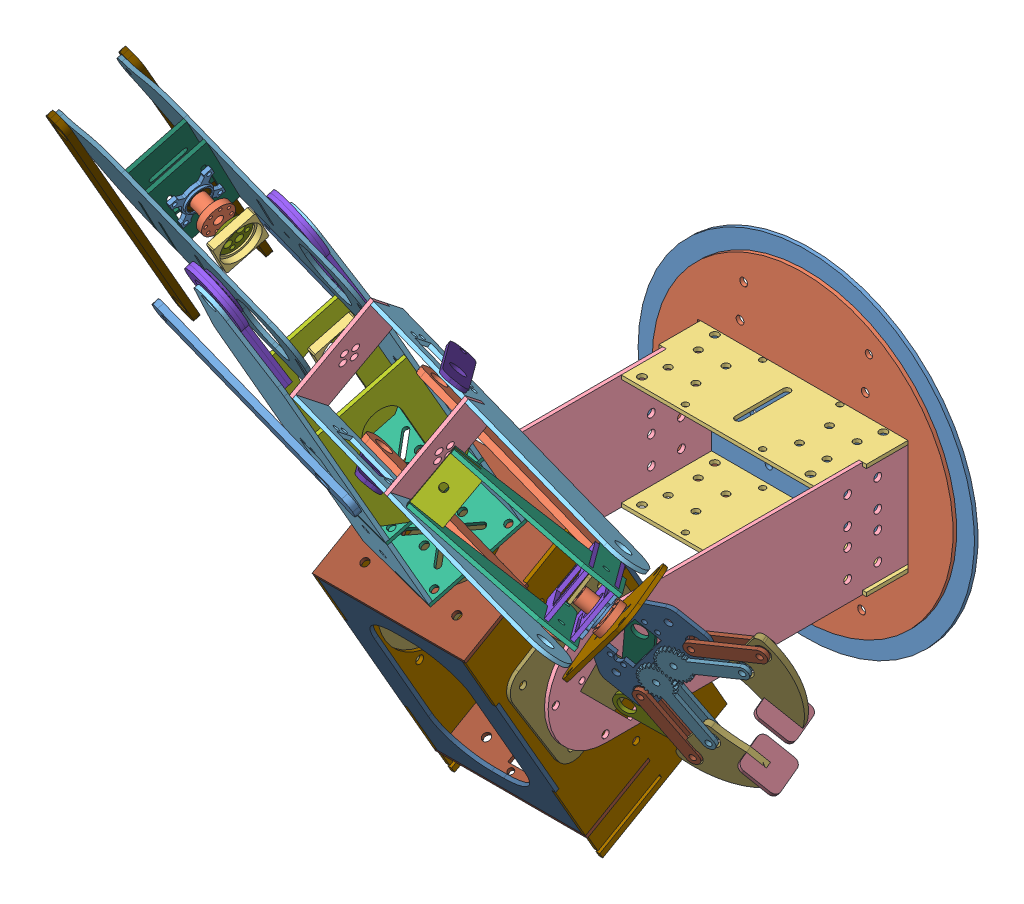
SolidWorks assembly arm, configuration Default. Lengths in mm.
Overall size (626.3 598.27 562.11).
77 component instances, 38 part files, 173 mates.
Components (placement in the parent):
- base2-1: base2 [Default] at origin size (279.4 279.4 3)
- base1-2: base1 [Default] at (0 0 3) size (250 250 3)
- base3-1: base3 [Default] at (1.3 -44.4 40.5) x (1 0 0) z (0 -1 0) size (172.4 75 3.1)
- base4-1: base4 [Default] at (81.3 0.125 254.1969) x (0 0 -1) z (1 0 0) size (298.82 95.25 3.1)
- base3-3: base3 [Default] at (1.3 47.75 40.5) x (1 0 0) z (0 -1 0) size (172.4 75 3.1)
- base4-3: base4 [Default] at (-81.8 0.14 254.1969) x (0 0 -1) z (1 0 0) size (298.82 95.25 3.1)
- upper_arm1-1: upper_arm1 [Default] at (-4.9605 223.8593 421.726) x (-0.978247 0.103059 -0.180031) z (-0.207442 -0.486002 0.848982) size (70 324.63 3.1)
- upper_arm2_(1,2)-1: upper_arm2_(1,2) [motor] at (2.3 89.3627 305.2813) x (0.207442 0.486002 -0.848982) z (0 0.86786 0.496809) size (76.2 70 3.1)
- upper_arm3-1: upper_arm3 [Default] at (36.5387 202.9167 378.6516) x (0 -0.86786 -0.496809) z (-0.978247 0.103059 -0.180031) size (120 70 3.1)
- upper_arm4-1: upper_arm4 [Default] at (-4.9605 344.9909 491.0681) x (0.978146 -0.115516 0.172876) z (0.207442 0.486002 -0.848982) size (70 90 3.1)
- shoulder1-1: shoulder1 [Default] at (-60.8 0.125 254.1969) x (0 -0.86786 -0.496809) z (1 0 0) size (230.3 120 3.1)
- shoulder2-1: shoulder2 [Default] at (2.3 21.537 197.3187) x (0 -0.86786 -0.496809) z (0 -0.496809 0.86786) size (200 126.2 3.1)
- shoulder3_(1,2)-1: shoulder3_(1,2) [motor] at (2.3 -97.7479 198.1693) x (1 0 0) z (0 0.86786 0.496809) size (126.2 120 3.1)
- shoulder1-2: shoulder1 [Default] at (62.3 0.125 254.1969) x (0 -0.86786 -0.496809) z (1 0 0) size (230.3 120 3.1)
- shoulder2-2: shoulder2 [Default] at (2.3 -38.0801 301.4619) x (0 -0.86786 -0.496809) z (0 0.496809 -0.86786) size (200 126.2 3.1)
- shoulder3_(1,2)-2: shoulder3_(1,2) [Default] at (2.3 78.5145 299.0712) x (1 0 0) z (0 0.86786 0.496809) size (126.2 120 3.1)
- upper_arm1-2: upper_arm1 [Default] at (10.2036 259.386 359.6655) x (-0.978247 0.103059 -0.180031) z (-0.207442 -0.486002 0.848982) size (70 324.63 3.1)
- upper_arm2_(1,2)-2: upper_arm2_(1,2) [motor] at (2.3 154.4522 342.5419) x (-0.207442 -0.486002 0.848982) z (0 -0.86786 -0.496809) size (76.2 70 3.1)
- upper_arm3-2: upper_arm3 [Default] at (-28.9061 209.8114 366.6075) x (0 -0.86786 -0.496809) z (-0.978247 0.103059 -0.180031) size (120 70 3.1)
- upper_arm4-2: upper_arm4 [Default] at (8.9174 377.5044 434.2712) x (0.978146 -0.115516 0.172876) z (0.207442 0.486002 -0.848982) size (70 90 3.1)
- upper_arm4-3: upper_arm4 [Default] at (-4.3382 346.4489 488.5212) x (0.978146 -0.115516 0.172876) z (0.207442 0.486002 -0.848982) size (70 90 3.1)
- upper_arm4-4: upper_arm4 [Default] at (8.2951 376.0464 436.8182) x (0.978146 -0.115516 0.172876) z (0.207442 0.486002 -0.848982) size (70 90 3.1)
- shoulder4-1: shoulder4 [Default] at (68.5 0.125 254.1969) x (0 0.849314 0.527888) z (-1 0 0) size (100 100 3.1)
- shoulder5-1: shoulder5 [Default] at (2.3 -51.6645 224.5499) x (-0.978247 0.103059 -0.180031) z (0 -0.86786 -0.496809) size (55 55 3.1)
- shoulder4-2: shoulder4 [Default] at (-60.8 0.125 254.1969) x (0 0.849314 0.527888) z (-1 0 0) size (100 100 3.1)
- elbow1-1: elbow1 [Default] at (7.0981 373.2422 441.7168) x (-0.962178 0.258021 -0.087396) z (0.207442 0.486002 -0.848982) size (242.23 80.88 3.1)
- elbow1-2: elbow1 [Default] at (-3.0728 349.4135 483.3424) x (-0.962178 0.258021 -0.087396) z (0.207442 0.486002 -0.848982) size (242.23 80.88 3.1)
- elbow2_(1,2)-1: elbow2_(1,2) [Default] at (-55.3424 377.9384 456.1984) x (-0.207442 -0.486002 0.848982) z (-0.962178 0.258021 -0.087396) size (52.13 80 3.1)
- elbow2_(1,2)-2: elbow2_(1,2) [motor] at (-76.7809 383.2969 454.0275) x (0.207442 0.486002 -0.848982) z (0.962178 -0.258021 0.087396) size (52.13 80 3.1)
- elbow3_(1,2,3)-1: elbow3_(1,2,3) [to hub] at (-21.594 368.8883 459.2638) x (0.098688 0.629162 0.770984) z (0.962178 -0.258021 0.087396) size (30 30 3.1)
- 1 x 1.245 super thin bearing-1: 1 x 1.245 super thin bearing [Default] at (-3.0728 349.4135 483.3424) x (-0.888922 -0.268661 -0.370997) z (-0.408394 0.831639 0.376286) size (32.96 6.35 32.96)
- 1 x 1.245 super thin bearing-2: 1 x 1.245 super thin bearing [Default] at (7.7412 374.7488 439.085) x (-0.313259 0.855162 0.412997) z (-0.926734 -0.180278 -0.329641) size (32.96 6.35 32.96)
- bearing mount-2: bearing mount [Default] at (-55.3424 377.9384 456.1984) x (-0.207442 -0.486002 0.848982) z (0.17658 0.835001 0.521145) size (33.27 5.08 33.27)
  - .5 x .75 non flanged bearing-1: .5 x .75 non flanged bearing [Default] at origin size (19.05 3.91 19.05)
  - 535118-1: 535118 [Default] at origin size (33.27 5.08 33.27)
- servo shaft hub-2: servo shaft hub [Default] at (-33.0439 371.9587 458.2238) x (0.109763 0.073566 -0.991232) z (0.249329 0.963334 0.099104) size (25.39 25.4 25.39)
- bearing_mount2-1: bearing_mount2 [Default] at (-18.6112 368.0884 459.5347) x (0.207442 0.486002 -0.848982) z (-0.17658 -0.835001 -0.521145) size (33.53 6.35 33.53)
  - 535178-1: 535178 [Default] at origin size (33.53 6.35 33.53)
- bearing_mount2-2: bearing_mount2 [Default] at (73.8301 343.299 467.9313) x (-0.207442 -0.486002 0.848982) z (0.17658 0.835001 0.521145) size (33.53 6.35 33.53)
  - 535178-1: 535178 [Default] at origin size (33.53 6.35 33.53)
- forearm1-1: forearm1 [Default] at (83.4518 340.7188 468.8053) x (-0.253916 -0.733199 0.630829) z (0.962178 -0.258021 0.087396) size (76.2 40 3.1)
- forearm2-1: forearm2 [Default] at (309.4718 310.6377 464.4217) x (0.098688 0.629162 0.770984) z (-0.253916 -0.733199 0.630829) size (40 244.85 3.1)
- forearm1-2: forearm1 [Default] at (169.9036 317.5356 476.6578) x (-0.253916 -0.733199 0.630829) z (0.962178 -0.258021 0.087396) size (76.2 40 3.1)
- forearm2-2: forearm2 [Default] at (290.9106 257.0408 510.5353) x (0.098688 0.629162 0.770984) z (-0.253916 -0.733199 0.630829) size (40 244.85 3.1)
- wrist1-1: wrist1 [Default] at (298.5103 268.6492 508.2224) x (-0.750272 0.560917 0.349948) z (0.253916 0.733199 -0.630829) size (128.8 82.5 3.1)
- wrist3-1: wrist3 [Default] at (222.263 341.4185 526.4428) x (-0.253916 -0.733199 0.630829) z (-0.610425 -0.384436 -0.692525) size (45 25 3.1)
- wrist1-2: wrist1 [Default] at (309.1494 299.3702 481.7906) x (-0.750272 0.560917 0.349948) z (0.253916 0.733199 -0.630829) size (128.8 82.5 3.1)
- wrist2_(1,2)-1: wrist2_(1,2) [motor] at (292.4858 286.2281 490.5617) x (-0.253916 -0.733199 0.630829) z (-0.750272 0.560917 0.349948) size (45 64.15 3.1)
- wrist2_(1,2)-2: wrist2_(1,2) [bearing] at (307.1161 275.2902 483.7377) x (-0.253916 -0.733199 0.630829) z (-0.750272 0.560917 0.349948) size (45 64.15 3.1)
- bearing mount-3: bearing mount [Default] at (307.1161 275.2902 483.7377) x (0.610425 0.384436 0.692525) z (0.253916 0.733199 -0.630829) size (33.27 5.08 33.27)
  - .5 x .75 non flanged bearing-1: .5 x .75 non flanged bearing [Default] at origin size (19.05 3.91 19.05)
  - 535118-1: 535118 [Default] at origin size (33.27 5.08 33.27)
- servo shaft hub-3: servo shaft hub [Default] at (316.0444 268.6153 479.5733) x (0.262088 -0.233607 0.936343) z (-0.606961 -0.794229 -0.028259) size (25.39 25.4 25.39)
- palm1-1: palm1 [Default] at (318.3702 266.8764 478.4885) x (-0.606961 -0.794229 -0.028259) z (-0.750272 0.560917 0.349948) size (100 55 3.1)
- palm2-1: palm2 [both] at (351.7256 241.9977 461.2898) x (0.606961 0.794229 0.028259) z (0.262088 -0.233607 0.936343) size (100.8 53.1 3.1)
- finger1-1: finger1 [Default] at (393.6016 281.5361 456.122) x (-0.943314 -0.266753 0.197488) z (0.262088 -0.233607 0.936343) size (61 11 3.1)
- finger2-1: finger2 [Default] at (355.5853 192.3989 447.8351) x (0.606937 0.794247 0.02827) z (0.262088 -0.233607 0.936343) size (48 59.12 5)
- finger3-1: finger3 [Default] at (401.3889 186.3667 435.1648) x (0.262088 -0.233607 0.936343) z (-0.606937 -0.794247 -0.02827) size (30 30 3.1)
- finger1-2: finger1 [Default] at (396.3445 279.8039 466.8836) x (-0.943314 -0.266753 0.197488) z (-0.262088 0.233607 -0.936343) size (61 11 3.1)
- finger2-2: finger2 [Default] at (404.5054 278.5927 460.9863) x (-0.606937 -0.794247 -0.02827) z (-0.262088 0.233607 -0.936343) size (48 59.12 5)
- finger3-2: finger3 [Default] at (422.0015 237.3043 444.1327) x (-0.262088 0.233607 -0.936343) z (0.606937 0.794247 0.02827) size (30 30 3.1)
- finger4-1: finger4 [mirror] at (355.5613 254.7302 463.3927) x (-0.262444 0.916438 0.3021) z (-0.262088 0.233607 -0.936343) size (26.93 68.39 3.1)
- finger4-2: finger4 [mirror] at (356.8717 253.5621 468.0745) x (0.143981 -0.949934 -0.277299) z (0.262088 -0.233607 0.936343) size (26.93 68.39 3.1)
- finger4-3: finger4 [Default] at (341.6977 233.7064 467.368) x (-0.772398 -0.632447 0.058411) z (0.262088 -0.233607 0.936343) size (26.93 68.39 3.1)
- finger4-4: finger4 [Default] at (339.5748 235.5986 459.7836) x (-0.772398 -0.632447 0.058411) z (0.262088 -0.233607 0.936343) size (26.93 68.39 3.1)
- finger1-3: finger1 [Default] at (340.443 194.4266 459.2009) x (-0.528901 0.776793 0.341843) z (-0.262088 0.233607 -0.936343) size (61 11 3.1)
- finger1-4: finger1 [Default] at (337.2422 196.0461 450.5686) x (-0.528901 0.776793 0.341843) z (0.262088 -0.233607 0.936343) size (61 11 3.1)
- link1-1: link1 [Default] at (312.9666 235.9861 453.3375) x (-0.240103 -0.955534 -0.171188) z (0.262088 -0.233607 0.936343) size (75 20 3.1)
- link2-1: link2 [Default] at (328.5353 184.6663 450.1666) x (-0.892444 0.310539 0.327276) z (-0.262088 0.233607 -0.936343) size (69 19 3.1)
- wrist_link2-1: wrist_link2 [Default] at (144.768 345.1475 438.2364) x (-0.610425 -0.384436 -0.692525) z (0.253916 0.733199 -0.630829) size (85 20 3.1)
- elbow_link1-1: elbow_link1 [Default] at (-148.4367 298.9006 424.797) x (0 -0.86786 -0.496809) z (0.207442 0.486002 -0.848982) size (225.8 20 5)
- elbow_link2-1: elbow_link2 [Default] at (-68.1451 186.6836 388.6575) x (-0.962178 0.258021 -0.087396) z (-0.207442 -0.486002 0.848982) size (190 20 5)
- elbow_link1-2: elbow_link1 [Default] at (-135.5483 329.0959 372.0498) x (0 0.86786 0.496809) z (-0.207442 -0.486002 0.848982) size (225.8 20 5)
- elbow_link2-2: elbow_link2 [Default] at (-51.3008 226.147 319.7201) x (-0.962178 0.258021 -0.087396) z (-0.207442 -0.486002 0.848982) size (190 20 5)
- wrist_link1-3: wrist_link1 [Default] at (183.8975 259.8538 467.7188) x (0.962178 -0.258021 0.087396) z (-0.253916 -0.733199 0.630829) size (185.8 20 5)
- wrist_link2-3: wrist_link2 [Default] at (125.4196 289.2778 486.3056) x (-0.610425 -0.384436 -0.692525) z (-0.253916 -0.733199 0.630829) size (85 20 3.1)
- wrist_link1-4: wrist_link1 [Default] at (195.8062 294.2408 438.1329) x (0.962178 -0.258021 0.087396) z (0.253916 0.733199 -0.630829) size (185.8 20 5)
Mates (geometry in assembly coordinates):
- Concentric1: concentric: circle of base2-1; circle of base1-2
- Concentric2: concentric: circle of base2-1; circle of base1-2
- Coincident1: coincident aligned: plane of base2-1 through (0 0 3) normal (0 0 1); circle of base1-2
- Coincident2: coincident: line of base1-2 through (-87.5 -47.5 3) axis (1 0 0); line of base3-1 through (-84.9 -47.5 3) axis (1 0 0)
- Coincident3: coincident: plane of base1-2 through (-87.5 -47.5 6) normal (0 1 0); plane of base3-1 through (1.3 -47.5 40.5) normal (0 -1 0)
- Coincident4: coincident: line of base1-2 through (87.5 -47.5 6) axis (0 1 0); plane of base3-1 through (87.5 -44.4 40.5) normal (1 0 0)
- Coincident7: coincident: plane of base2-1 through (0 0 3) normal (0 0 1); line of base4-1 through (84.4 -44.4 3) axis (0 1 0)
- Coincident8: coincident: line of base3-1 through (81.3 -47.5 40.5) axis (0 0 1); line of base4-1 through (81.3 -47.5 254.1969) axis (0 0 -1)
- Parallel1: parallel: line of base1-2 through (87.5 -47.5 6) axis (0 1 0); line of base4-1 through (84.4 -44.4 3) axis (0 1 0)
- Coincident10: coincident anti-aligned: plane of base2-1 through (0 0 3) normal (0 0 1); plane of base3-3 through (-78.7 44.65 3) normal (0 0 -1)
- Coincident11: coincident aligned: line of base4-1 through (81.3 44.65 3) axis (0 0 1); line of base3-3 through (81.3 44.65 40.5) axis (0 0 1)
- Coincident13: coincident anti-aligned: line of base3-3 through (-78.7 47.75 40.5) axis (-1 0 0); line of base4-3 through (-81.8 47.75 40.5) axis (1 0 0)
- Coincident14: coincident anti-aligned: line of base3-3 through (-78.7 47.75 78) axis (0 0 -1); line of base4-3 through (-78.7 47.75 40.5) axis (0 0 1)
- Coincident15: coincident: line of shoulder1-1 through (-57.7 63.3899 224.8495) axis (0 -0.86786 -0.496809); plane of shoulder2-1 through (2.3 19.9969 200.0091) normal (0 -0.496809 0.86786)
- Coincident16: coincident anti-aligned: line of shoulder1-1 through (-57.7 -23.3961 175.1686) axis (0 0.496809 -0.86786); line of shoulder2-1 through (-57.7 -21.856 172.4783) axis (0 -0.496809 0.86786)
- Coincident17: coincident: plane of shoulder1-1 through (-57.7 0.125 254.1969) normal (1 0 0); line of shoulder3_(1,2)-1 through (-57.7 -65.249 147.6378) axis (0 -0.496809 0.86786)
- Coincident18: coincident anti-aligned: line of shoulder1-1 through (-60.8 -95.0575 199.7094) axis (1 0 0); line of shoulder3_(1,2)-1 through (-57.7 -95.0575 199.7094) axis (-1 0 0)
- Coincident19: coincident aligned: line of shoulder1-1 through (-60.8 -79.933 273.9311) axis (0 0.86786 0.496809); line of shoulder2-2 through (-60.8 -79.933 273.9311) axis (0 0.86786 0.496809)
- Coincident20: coincident anti-aligned: plane of shoulder1-1 through (-60.8 6.853 323.612) normal (0 -0.496809 0.86786); plane of shoulder2-2 through (2.3 -36.54 298.7715) normal (0 0.496809 -0.86786)
- Coincident21: coincident aligned: line of shoulder1-1 through (-60.8 5.3129 326.3023) axis (1 0 0); line of shoulder2-2 through (-60.8 5.3129 326.3023) axis (1 0 0)
- Coincident22: coincident anti-aligned: line of shoulder1-2 through (65.4 -79.933 273.9311) axis (0 0.86786 0.496809); line of shoulder2-2 through (65.4 6.853 323.612) axis (0 -0.86786 -0.496809)
- Coincident23: coincident aligned: line of shoulder1-2 through (62.3 5.3129 326.3023) axis (1 0 0); line of shoulder2-2 through (62.3 5.3129 326.3023) axis (1 0 0)
- Coincident24: coincident anti-aligned: line of shoulder1-2 through (62.3 81.2048 300.6113) axis (1 0 0); line of shoulder3_(1,2)-2 through (65.4 81.2048 300.6113) axis (-1 0 0)
- Coincident25: coincident anti-aligned: line of shoulder1-2 through (65.4 78.5145 299.0712) axis (0 -0.496809 0.86786); line of shoulder3_(1,2)-2 through (65.4 48.7059 351.1428) axis (0 0.496809 -0.86786)
- Coincident28: coincident anti-aligned: line of shoulder2-1 through (65.4 -21.856 172.4783) axis (0 -0.496809 0.86786); line of shoulder1-2 through (65.4 -23.3961 175.1686) axis (0 0.496809 -0.86786)
- Coincident29: coincident anti-aligned: line of shoulder3_(1,2)-1 through (65.4 -127.5564 250.2409) axis (0 0.496809 -0.86786); line of shoulder1-2 through (65.4 -97.7479 198.1693) axis (0 -0.496809 0.86786)
- Concentric4: concentric: circle of base4-1; circle of shoulder1-2
- Distance1: distance = 19 mm: plane of shoulder1-2 through (65.4 0.125 254.1969) normal (1 0 0); plane of base4-1 through (84.4 0.125 254.1969) normal (1 0 0)
- Coincident31: coincident aligned: line of upper_arm1-1 through (-4.9605 72.3526 334.9956) axis (-0.207442 -0.486002 0.848982); line of upper_arm2_(1,2)-1 through (10.2036 107.8794 272.9351) axis (-0.207442 -0.486002 0.848982)
- Coincident32: coincident: plane of upper_arm1-1 through (29.2782 71.4359 342.8368) normal (0 -0.86786 -0.496809); plane of upper_arm2_(1,2)-1 through (2.3 92.0531 306.8214) normal (0 0.86786 0.496809)
- Coincident33: coincident anti-aligned: line of upper_arm1-1 through (28.6351 69.9293 345.4687) axis (-0.978247 0.103059 -0.180031); line of upper_arm2_(1,2)-1 through (-5.6036 73.5364 339.1676) axis (0.978247 -0.103059 0.180031)
- Coincident34: coincident aligned: line of upper_arm1-1 through (28.6351 132.3285 381.1892) axis (-0.978247 0.103059 -0.180031); line of upper_arm2_(1,2)-2 through (28.6351 132.3285 381.1892) axis (-0.978247 0.103059 -0.180031)
- Coincident35: coincident aligned: line of upper_arm1-1 through (-5.6036 135.9355 374.8881) axis (0 -0.86786 -0.496809); line of upper_arm2_(1,2)-2 through (-5.6036 135.9355 374.8881) axis (0 -0.86786 -0.496809)
- Coincident36: coincident anti-aligned: line of upper_arm1-2 through (44.4422 169.3618 316.4968) axis (-0.978247 0.103059 -0.180031); line of upper_arm2_(1,2)-2 through (10.2036 172.9689 310.1957) axis (0.978247 -0.103059 0.180031)
- Coincident37: coincident anti-aligned: line of upper_arm2_(1,2)-1 through (10.2036 107.8794 272.9351) axis (0 0.86786 0.496809); line of upper_arm1-2 through (10.2036 110.5697 274.4752) axis (0 -0.86786 -0.496809)
- Coincident38: coincident aligned: line of upper_arm1-1 through (29.2782 133.8351 378.5574) axis (0 0.86786 0.496809); line of upper_arm3-1 through (29.2782 146.853 386.0095) axis (0 0.86786 0.496809)
- Coincident39: coincident aligned: line of upper_arm3-1 through (40.6875 160.5652 331.8634) axis (-0.207442 -0.486002 0.848982); line of upper_arm2_(1,2)-2 through (43.7991 167.8552 319.1287) axis (-0.207442 -0.486002 0.848982)
- Coincident40: coincident aligned: line of upper_arm2_(1,2)-2 through (-24.6782 175.0693 306.5265) axis (-0.207442 -0.486002 0.848982); line of upper_arm3-2 through (-27.7898 167.7793 319.2612) axis (-0.207442 -0.486002 0.848982)
- Coincident41: coincident anti-aligned: line of upper_arm1-1 through (-39.1991 288.2688 450.2314) axis (0 -0.86786 -0.496809); line of upper_arm3-2 through (-39.1991 154.0671 373.4074) axis (0 0.86786 0.496809)
- Concentric5: concentric anti-aligned: circle of upper_arm1-1; circle of upper_arm4-2
- Coincident44: coincident anti-aligned: plane of upper_arm1-2 through (9.5605 257.8794 362.2973) normal (-0.207442 -0.486002 0.848982); plane of upper_arm4-2 through (9.5605 379.011 431.6394) normal (0.207442 0.486002 -0.848982)
- Parallel4: parallel aligned: line of upper_arm1-2 through (-23.3782 329.8149 395.4287) axis (0.287924 0.799085 0.52779); line of upper_arm4-2 through (-26.2311 325.2386 395.7633) axis (0.287924 0.799085 0.52779)
- Coincident46: coincident anti-aligned: plane of upper_arm1-1 through (-4.9605 223.8593 421.726) normal (0.207442 0.486002 -0.848982); plane of upper_arm4-1 through (-4.9605 344.9909 491.0681) normal (-0.207442 -0.486002 0.848982)
- Concentric6: concentric anti-aligned: circle of upper_arm1-1; circle of upper_arm4-1
- Parallel5: parallel aligned: line of upper_arm1-1 through (-37.8992 295.7948 454.8574) axis (0.287924 0.799085 0.52779); line of upper_arm4-1 through (-39.466 294.2317 449.9283) axis (0.287924 0.799085 0.52779)
- Concentric7: concentric aligned: circle of upper_arm2_(1,2)-1; circle of shoulder3_(1,2)-2
- Distance2: distance = 12.5 mm: plane of upper_arm2_(1,2)-1 through (2.3 92.0531 306.8214) normal (0 0.86786 0.496809); plane of shoulder3_(1,2)-2 through (2.3 81.2048 300.6113) normal (0 0.86786 0.496809)
- Concentric8: concentric anti-aligned: circle of shoulder1-2; circle of shoulder4-1
- Coincident51: coincident: plane of shoulder1-2 through (65.4 0.125 254.1969) normal (1 0 0); line of shoulder4-1 through (65.4 56.2454 230.2073) axis (0 -0.849314 -0.527888)
- Concentric9: concentric anti-aligned: circle of shoulder1-2; circle of shoulder4-1
- Concentric10: concentric anti-aligned: circle of shoulder1-1; circle of shoulder4-2
- Concentric12: concentric anti-aligned: circle of shoulder1-1; circle of shoulder4-2
- Coincident52: coincident: plane of shoulder1-1 through (-60.8 0.125 254.1969) normal (-1 0 0); line of shoulder4-2 through (-60.8 24.1146 310.3173) axis (0 0.527888 -0.849314)
- Concentric15: concentric anti-aligned: circle of upper_arm2_(1,2)-1; circle of shoulder5-1
- Concentric18: concentric aligned: circle of shoulder3_(1,2)-2; circle of shoulder5-1
- Distance3: distance = 50 mm aligned: plane of shoulder5-1 through (2.3 -54.3549 223.0098) normal (0 -0.86786 -0.496809); plane of shoulder3_(1,2)-1 through (2.3 -97.7479 198.1693) normal (0 -0.86786 -0.496809)
- Coincident61: coincident anti-aligned: line of elbow1-1 through (-60.0595 357.6363 412.7223) axis (0.17658 0.835001 0.521145); line of elbow2_(1,2)-1 through (-53.0676 390.6993 433.3577) axis (-0.17658 -0.835001 -0.521145)
- Coincident62: coincident aligned: line of elbow1-1 through (-53.0676 390.6993 433.3577) axis (0.962178 -0.258021 0.087396); line of elbow2_(1,2)-1 through (-53.0676 390.6993 433.3577) axis (0.962178 -0.258021 0.087396)
- Coincident63: coincident anti-aligned: line of elbow1-1 through (-71.3739 395.9645 431.8988) axis (0.962178 -0.258021 0.087396); line of elbow2_(1,2)-2 through (-68.3911 395.1647 432.1697) axis (-0.962178 0.258021 -0.087396)
- Coincident64: coincident anti-aligned: line of elbow1-1 through (-71.3739 395.9645 431.8988) axis (-0.17658 -0.835001 -0.521145); line of elbow2_(1,2)-2 through (-78.4371 362.5645 411.053) axis (0.17658 0.835001 0.521145)
- Coincident65: coincident aligned: line of elbow1-2 through (-82.1879 370.6293 476.1562) axis (-0.17658 -0.835001 -0.521145); line of elbow2_(1,2)-2 through (-82.1879 370.6293 476.1562) axis (-0.17658 -0.835001 -0.521145)
- Coincident66: coincident anti-aligned: line of elbow1-2 through (-82.1879 370.6293 476.1562) axis (0.962178 -0.258021 0.087396); line of elbow2_(1,2)-2 through (-79.2051 369.8294 476.4272) axis (-0.962178 0.258021 -0.087396)
- Concentric19: concentric anti-aligned: circle of upper_arm1-2; circle of elbow1-1
- Distance4: distance = 3 mm: plane of upper_arm4-3 through (-3.6951 347.9555 485.8893) normal (0.207442 0.486002 -0.848982); plane of elbow1-2 through (-3.0728 349.4135 483.3424) normal (-0.207442 -0.486002 0.848982)
- Concentric20: concentric anti-aligned: cylinder of upper_arm4-2 through (9.5605 379.011 431.6394) axis (-0.207442 -0.486002 0.848982) radius 15.8115; cylinder of 1 x 1.245 super thin bearing-1 through (-4.39 346.3274 488.7334) axis (0.207442 0.486002 -0.848982) radius 15.8115
- Coincident67: coincident anti-aligned: plane of elbow1-2 through (-3.0728 349.4135 483.3424) normal (-0.207442 -0.486002 0.848982); plane of 1 x 1.245 super thin bearing-1 through (-3.0728 349.4135 483.3424) normal (0.207442 0.486002 -0.848982)
- Concentric22: concentric aligned: cylinder of upper_arm4-2 through (9.5605 379.011 431.6394) axis (-0.207442 -0.486002 0.848982) radius 15.8115; cylinder of 1 x 1.245 super thin bearing-2 through (9.0585 377.8349 433.6939) axis (-0.207442 -0.486002 0.848982) radius 15.8115
- Coincident68: coincident aligned: plane of elbow1-1 through (7.7412 374.7488 439.085) normal (0.207442 0.486002 -0.848982); circle of 1 x 1.245 super thin bearing-2
- Concentric24: concentric: circle of elbow2_(1,2)-1; circle of bearing mount-2/535118-1
- Parallel6: parallel aligned: line of elbow2_(1,2)-1 through (-48.8717 400.8798 452.69) axis (-0.17658 -0.835001 -0.521145); line of bearing mount-2/535118-1 through (-50.6752 376.5091 436.9241) axis (-0.17658 -0.835001 -0.521145)
- Coincident72: coincident: plane of elbow2_(1,2)-1 through (-55.3424 377.9384 456.1984) normal (0.962178 -0.258021 0.087396); line of bearing mount-2/535118-1 through (-61.705 356.0226 461.5448) axis (0.207442 0.486002 -0.848982)
- Concentric25: concentric anti-aligned: circle of bearing mount-2/535118-1; circle of servo shaft hub-2
- Distance5: distance = 20 mm: plane of servo shaft hub-2 through (-33.0439 371.9587 458.2238) normal (0.962178 -0.258021 0.087396); plane of bearing mount-2/535118-1 through (-52.2875 377.1191 456.4758) normal (0.962178 -0.258021 0.087396)
- Concentric26: concentric aligned: circle of elbow3_(1,2,3)-1; circle of servo shaft hub-2
- Concentric29: concentric anti-aligned: circle of elbow3_(1,2,3)-1; circle of servo shaft hub-2
- Distance6: distance = 15 mm: plane of elbow3_(1,2,3)-1 through (-18.6112 368.0884 459.5347) normal (0.962178 -0.258021 0.087396); plane of servo shaft hub-2 through (-33.0439 371.9587 458.2238) normal (0.962178 -0.258021 0.087396)
- Concentric43: concentric aligned: circle of elbow3_(1,2,3)-1; cylinder of ? through (3.1095 -6.5179 671.5444) axis (-0.048359 0.998803 -0.007319) radius 12.7
- Parallel11: parallel anti-aligned: plane of elbow1-2 through (-2.4297 350.9201 480.7105) normal (0.207442 0.486002 -0.848982); plane of bearing_mount2-1/535178-1 through (-18.9391 344.3047 465.5855) normal (-0.207442 -0.486002 0.848982)
- Coincident96: coincident aligned: plane of elbow3_(1,2,3)-1 through (-18.6112 368.0884 459.5347) normal (0.962178 -0.258021 0.087396); circle of bearing_mount2-1/535178-1
- Coincident101: coincident aligned: plane of elbow3_(1,2,3)-1; circle of ?
- Parallel13: parallel anti-aligned: line of elbow1-1 through (75.4008 342.5138 437.1641) axis (0.17658 0.835001 0.521145); line of bearing_mount2-2/535178-1 through (80.0884 364.596 461.9059) axis (-0.17658 -0.835001 -0.521145)
- Concentric47: concentric aligned: circle of ?; circle of ?
- Distance7: distance = 95 mm aligned: plane of ? through (-1.7918 94.7108 670.8026) normal (-0.048359 0.998803 -0.007319); plane of ? through (2.8024 -0.1755 671.4979) normal (-0.048359 0.998803 -0.007319)
- Concentric52: concentric: circle of elbow3_(1,2,3)-1; circle of forearm1-1
- Concentric53: concentric aligned: circle of elbow3_(1,2,3)-1; circle of forearm1-1
- Distance10: distance = 2 mm: plane of forearm1-1 through (83.4518 340.7188 468.8053) normal (-0.962178 0.258021 -0.087396); plane of elbow1-2 through (69.6222 296.3043 467.0509) normal (0.962178 -0.258021 0.087396)
- Coincident117: coincident: line of forearm1-1 through (93.1261 368.6537 444.7707) axis (0.962178 -0.258021 0.087396); line of forearm2-1 through (93.1261 368.6537 444.7707) axis (0.962178 -0.258021 0.087396)
- Coincident118: coincident: line of forearm1-1 through (96.1088 367.8538 445.0416) axis (0.098688 0.629162 0.770984); line of forearm2-1 through (96.1088 367.8538 445.0416) axis (0.098688 0.629162 0.770984)
- Coincident119: coincident aligned: line of forearm2-1 through (182.5605 344.6707 452.8941) axis (0.098688 0.629162 0.770984); line of forearm1-2 through (182.5605 344.6707 452.8941) axis (0.098688 0.629162 0.770984)
- Coincident120: coincident aligned: line of forearm2-1 through (179.5778 345.4705 452.6232) axis (0.962178 -0.258021 0.087396); line of forearm1-2 through (179.5778 345.4705 452.6232) axis (0.962178 -0.258021 0.087396)
- Coincident121: coincident: line of forearm1-1 through (73.7776 312.7839 492.8399) axis (0.962178 -0.258021 0.087396); line of forearm2-2 through (73.7776 312.7839 492.8399) axis (0.962178 -0.258021 0.087396)
- Coincident122: coincident: line of forearm1-2 through (162.2031 302.184 516.1121) axis (-0.098688 -0.629162 -0.770984); line of forearm2-2 through (162.2031 302.184 516.1121) axis (-0.098688 -0.629162 -0.770984)
- Coincident123: coincident anti-aligned: line of wrist1-2 through (282.5155 275.8996 438.8766) axis (0.610425 0.384436 0.692525); line of wrist2_(1,2)-2 through (325.2452 302.8102 487.3534) axis (-0.610425 -0.384436 -0.692525)
- Coincident124: coincident anti-aligned: line of wrist1-2 through (325.2452 302.8102 487.3534) axis (0.750272 -0.560917 -0.349948); line of wrist2_(1,2)-2 through (327.571 301.0713 486.2685) axis (-0.750272 0.560917 0.349948)
- Coincident125: coincident anti-aligned: line of wrist1-2 through (289.25 300.2928 469.939) axis (0.610425 0.384436 0.692525); line of wrist2_(1,2)-1 through (310.6149 313.748 494.1774) axis (-0.610425 -0.384436 -0.692525)
- Coincident126: coincident anti-aligned: line of wrist1-2 through (310.6149 313.748 494.1774) axis (0.750272 -0.560917 -0.349948); line of wrist2_(1,2)-1 through (312.9407 312.0092 493.0925) axis (-0.750272 0.560917 0.349948)
- Coincident127: coincident: line of wrist1-1 through (271.0892 242.9057 467.2639) axis (0.610425 0.384436 0.692525); line of wrist2_(1,2)-2 through (274.6602 245.1546 471.3152) axis (0.610425 0.384436 0.692525)
- Coincident128: coincident: line of wrist1-1 through (313.8189 269.8162 515.7407) axis (0.750272 -0.560917 -0.349948); line of wrist2_(1,2)-2 through (316.1448 268.0774 514.6558) axis (-0.750272 0.560917 0.349948)
- Coincident129: coincident anti-aligned: line of wrist1-1 through (209.0472 330.5307 544.1359) axis (0.750272 -0.560917 -0.349948); line of wrist3-1 through (224.0526 319.3124 537.137) axis (-0.750272 0.560917 0.349948)
- Coincident130: coincident anti-aligned: line of wrist1-1 through (224.0526 319.3124 537.137) axis (-0.610425 -0.384436 -0.692525); line of wrist3-1 through (222.1603 318.1206 534.9901) axis (0.610425 0.384436 0.692525)
- Concentric54: concentric: circle of wrist2_(1,2)-2; circle of bearing mount-3/535118-1
- Coincident131: coincident: plane of wrist2_(1,2)-2 through (307.1161 275.2902 483.7377) normal (0.750272 -0.560917 -0.349948); line of bearing mount-3/535118-1 through (321.4639 293.7912 484.8443) axis (-0.253916 -0.733199 0.630829)
- Concentric55: concentric: circle of forearm2-2; circle of wrist1-1
- Distance11: distance = 15 mm: plane of forearm2-2 through (290.9106 257.0408 510.5353) normal (0.253916 0.733199 -0.630829); plane of wrist1-1 through (299.2975 270.9221 506.2668) normal (0.253916 0.733199 -0.630829)
- Parallel14: parallel aligned: line of wrist2_(1,2)-2 through (291.9132 256.8466 480.7057) axis (0.610425 0.384436 0.692525); line of bearing mount-3/535118-1 through (311.6308 265.3146 500.3337) axis (0.610425 0.384436 0.692525)
- Coincident134: coincident aligned: line of palm1-1 through (301.2766 248.3975 480.3182) axis (0.606961 0.794229 0.028259); line of palm2-1 through (301.2766 248.3975 480.3182) axis (0.606961 0.794229 0.028259)
- Coincident135: coincident anti-aligned: line of palm1-1 through (330.8122 288.8331 478.8285) axis (-0.606961 -0.794229 -0.028259); line of palm2-1 through (300.4641 249.1216 477.4155) axis (0.606961 0.794229 0.028259)
- Coincident136: coincident aligned: line of palm1-1 through (300.4641 249.1216 477.4155) axis (0.262088 -0.233607 0.936343); line of palm2-1 through (300.4641 249.1216 477.4155) axis (0.262088 -0.233607 0.936343)
- Concentric56: concentric: circle of servo shaft hub-3; circle of palm1-1
- Concentric57: concentric: circle of servo shaft hub-3; circle of palm1-1
- Coincident137: coincident aligned: circle of servo shaft hub-3; plane of palm1-1 through (316.0444 268.6153 479.5733) normal (-0.750272 0.560917 0.349948)
- Concentric58: concentric: cylinder of bearing mount-3/.5 x .75 non flanged bearing-1 through (310.0509 273.0961 482.3689) axis (-0.750272 0.560917 0.349948) radius 6.35; cylinder of servo shaft hub-3 through (296.9875 282.8626 488.462) axis (0.750272 -0.560917 -0.349948) radius 6.3462
- Distance12: distance = 15 mm: plane of palm1-1 through (318.3702 266.8764 478.4885) normal (0.750272 -0.560917 -0.349948); plane of wrist2_(1,2)-2 through (307.1161 275.2902 483.7377) normal (0.750272 -0.560917 -0.349948)
- Coincident141: coincident anti-aligned: line of finger2-1 through (399.1012 184.2666 433.6258) axis (0.750291 -0.560892 -0.349947); line of finger3-1 through (399.1012 184.2666 433.6258) axis (-0.750291 0.560892 0.349947)
- Coincident142: coincident aligned: line of finger2-1 through (402.2931 185.5607 438.3952) axis (-0.262088 0.233607 -0.936343); line of finger3-1 through (401.7952 186.0046 436.6161) axis (-0.262088 0.233607 -0.936343)
- Coincident143: coincident anti-aligned: line of finger2-2 through (424.2892 239.4043 445.6717) axis (0.750291 -0.560892 -0.349947); line of finger3-2 through (424.2892 239.4043 445.6717) axis (-0.750291 0.560892 0.349947)
- Coincident144: coincident aligned: line of finger2-2 through (421.0973 238.1102 440.9023) axis (0.262088 -0.233607 0.936343); line of finger3-2 through (421.5952 237.6664 442.6814) axis (0.262088 -0.233607 0.936343)
- Concentric59: concentric anti-aligned: circle of palm2-1; circle of finger4-1
- Coincident145: coincident anti-aligned: plane of palm2-1 through (351.7256 241.9977 461.2898) normal (-0.262088 0.233607 -0.936343); plane of finger4-1 through (367.6257 257.4146 460.6856) normal (0.262088 -0.233607 0.936343)
- Concentric60: concentric anti-aligned: circle of finger4-1; circle of finger4-2
- Concentric61: concentric anti-aligned: circle of finger4-1; circle of finger4-2
- Concentric62: concentric anti-aligned: circle of finger2-2; circle of finger4-2
- Coincident150: coincident anti-aligned: circle of finger2-2; plane of finger4-2 through (368.638 257.6159 465.7924) normal (-0.262088 0.233607 -0.936343)
- Coincident151: coincident: plane of finger2-2 through (375.4907 252.0808 457.1534) normal (-0.262088 0.233607 -0.936343); line of finger4-1 through (403.7453 263.3915 452.0666) axis (-0.943319 -0.26673 0.197495)
- Concentric63: concentric aligned: circle of palm2-1; circle of finger1-1
- Concentric64: concentric anti-aligned: circle of finger1-1; circle of finger2-2
- Coincident152: coincident: line of finger1-1 through (371.855 269.4425 462.5026) axis (0.943314 0.266753 -0.197488); plane of finger2-2 through (375.4907 252.0808 457.1534) normal (-0.262088 0.233607 -0.936343)
- Concentric65: concentric anti-aligned: circle of palm2-1; circle of finger1-2
- Concentric66: concentric anti-aligned: circle of finger1-1; circle of finger1-2
- Coincident154: coincident anti-aligned: plane of finger1-2 through (372.0454 273.4171 468.7808) normal (-0.262088 0.233607 -0.936343); circle of finger2-2
- Parallel17: parallel anti-aligned: plane of finger3-1 through (401.3889 186.3667 435.1648) normal (0.606937 0.794247 0.02827); plane of finger3-2 through (422.0015 237.3043 444.1327) normal (-0.606937 -0.794247 -0.02827)
- Concentric67: concentric aligned: circle of palm2-1; circle of finger4-4
- Concentric68: concentric aligned: circle of palm2-1; circle of finger4-3
- Concentric69: concentric aligned: circle of finger2-1; circle of finger4-3
- Coincident158: coincident anti-aligned: circle of finger2-1; plane of finger4-3 through (350.1415 225.3938 462.9306) normal (-0.262088 0.233607 -0.936343)
- Coincident159: coincident: plane of finger2-1 through (374.9496 226.3135 450.8762) normal (-0.262088 0.233607 -0.936343); line of finger4-4 through (342.9812 222.2129 458.8013) axis (0.528901 -0.776793 -0.341843)
- Coincident160: coincident: plane of palm2-1 through (351.7256 241.9977 461.2898) normal (-0.262088 0.233607 -0.936343); line of finger4-4 through (342.9812 222.2129 458.8013) axis (0.528901 -0.776793 -0.341843)
- Concentric70: concentric aligned: circle of finger2-1; circle of finger4-4
- Concentric71: concentric aligned: circle of palm2-1; circle of finger1-4
- Concentric72: concentric aligned: circle of finger2-1; circle of finger1-4
- Coincident161: coincident: plane of palm2-1 through (351.7256 241.9977 461.2898) normal (-0.262088 0.233607 -0.936343); line of finger1-4 through (320.7742 211.8017 462.4197) axis (0.528901 -0.776793 -0.341843)
- Concentric73: concentric anti-aligned: circle of finger1-3; circle of finger1-4
- Concentric74: concentric anti-aligned: circle of finger1-3; circle of finger1-4
- Coincident165: coincident: line of palm2-1 through (302.5474 215.7481 471.8168) axis (0.750272 -0.560917 -0.349948); plane of finger1-3 through (326.0263 214.2941 464.8822) normal (-0.262088 0.233607 -0.936343)
- Concentric75: concentric aligned: circle of palm2-1; circle of link1-1
- Concentric76: concentric anti-aligned: circle of link1-1; circle of link2-1
- Concentric77: concentric anti-aligned: circle of finger1-4; circle of link2-1
- Coincident166: coincident anti-aligned: plane of finger1-4 through (324.4014 215.7424 459.0769) normal (-0.262088 0.233607 -0.936343); plane of link2-1 through (306.2242 192.4297 458.3485) normal (0.262088 -0.233607 0.936343)
- Distance13: distance = 10 mm aligned: plane of link1-1 through (312.9666 235.9861 453.3375) normal (-0.262088 0.233607 -0.936343); plane of link2-1 through (305.4117 193.1539 455.4458) normal (-0.262088 0.233607 -0.936343)
- Concentric81: concentric: circle of forearm2-1; circle of wrist_link2-1
- Coincident171: coincident: line of forearm2-1 through (307.4981 298.0545 449.002) axis (-0.962178 0.258021 -0.087396); plane of wrist_link2-1 through (144.768 345.1475 438.2364) normal (-0.253916 -0.733199 0.630829)
- Concentric84: concentric aligned: circle of bearing_mount2-1/535178-1; circle of bearing_mount2-2/535178-1
- Concentric85: concentric aligned: circle of elbow3_(1,2,3)-1; circle of bearing_mount2-1/535178-1
- Distance14: distance = 10 mm aligned: plane of bearing_mount2-2/535178-1 through (73.8301 343.299 467.9313) normal (-0.962178 0.258021 -0.087396); plane of forearm1-1 through (83.4518 340.7188 468.8053) normal (-0.962178 0.258021 -0.087396)
- Concentric86: concentric aligned: circle of elbow1-2; circle of elbow_link1-1
- Coincident176: coincident: plane of elbow1-2 through (-3.0728 349.4135 483.3424) normal (-0.207442 -0.486002 0.848982); line of elbow_link1-1 through (-157.182 210.8888 366.3881) axis (0 0.86786 0.496809)
- Concentric87: concentric aligned: circle of upper_arm1-1; circle of elbow_link2-1
- Coincident177: coincident anti-aligned: plane of upper_arm1-1 through (-5.6036 222.3527 424.3579) normal (-0.207442 -0.486002 0.848982); circle of elbow_link2-1
- Concentric88: concentric anti-aligned: circle of elbow_link1-1; circle of elbow_link2-1
- Concentric89: concentric anti-aligned: circle of elbow1-1; circle of elbow_link1-2
- Coincident180: coincident anti-aligned: plane of elbow1-1 through (7.7412 374.7488 439.085) normal (0.207442 0.486002 -0.848982); plane of elbow_link1-2 through (-136.5855 326.6659 376.2947) normal (-0.207442 -0.486002 0.848982)
- Concentric90: concentric aligned: circle of upper_arm1-2; circle of elbow_link2-2
- Coincident181: coincident anti-aligned: plane of upper_arm1-2 through (10.2036 259.386 359.6655) normal (0.207442 0.486002 -0.848982); plane of elbow_link2-2 through (-52.338 223.717 323.9651) normal (-0.207442 -0.486002 0.848982)
- Concentric91: concentric aligned: circle of elbow_link1-2; circle of elbow_link2-2
- Concentric92: concentric: circle of wrist_link2-1; circle of wrist_link2-3
- Concentric93: concentric: circle of wrist_link2-1; circle of wrist_link2-3
- Coincident186: coincident: plane of forearm2-2 through (290.1234 254.7679 512.4909) normal (-0.253916 -0.733199 0.630829); line of wrist_link2-3 through (114.6824 272.1814 462.1131) axis (0.610425 0.384436 0.692525)
- Concentric94: concentric: circle of wrist_link1-3; circle of wrist_link2-3
- Coincident187: coincident: plane of wrist_link1-3 through (182.6279 256.1878 470.873) normal (-0.253916 -0.733199 0.630829); line of wrist_link2-3 through (114.6824 272.1814 462.1131) axis (0.610425 0.384436 0.692525)
- Concentric95: concentric: circle of wrist1-1; circle of wrist_link1-3
- Concentric96: concentric: circle of wrist_link2-1; circle of wrist_link1-4
- Coincident188: coincident: plane of wrist1-2 through (309.1494 299.3702 481.7906) normal (-0.253916 -0.733199 0.630829); plane of wrist_link1-4 through (197.0758 297.9068 434.9788) normal (0.253916 0.733199 -0.630829)
- Concentric97: concentric: circle of wrist1-2; circle of wrist_link1-4
